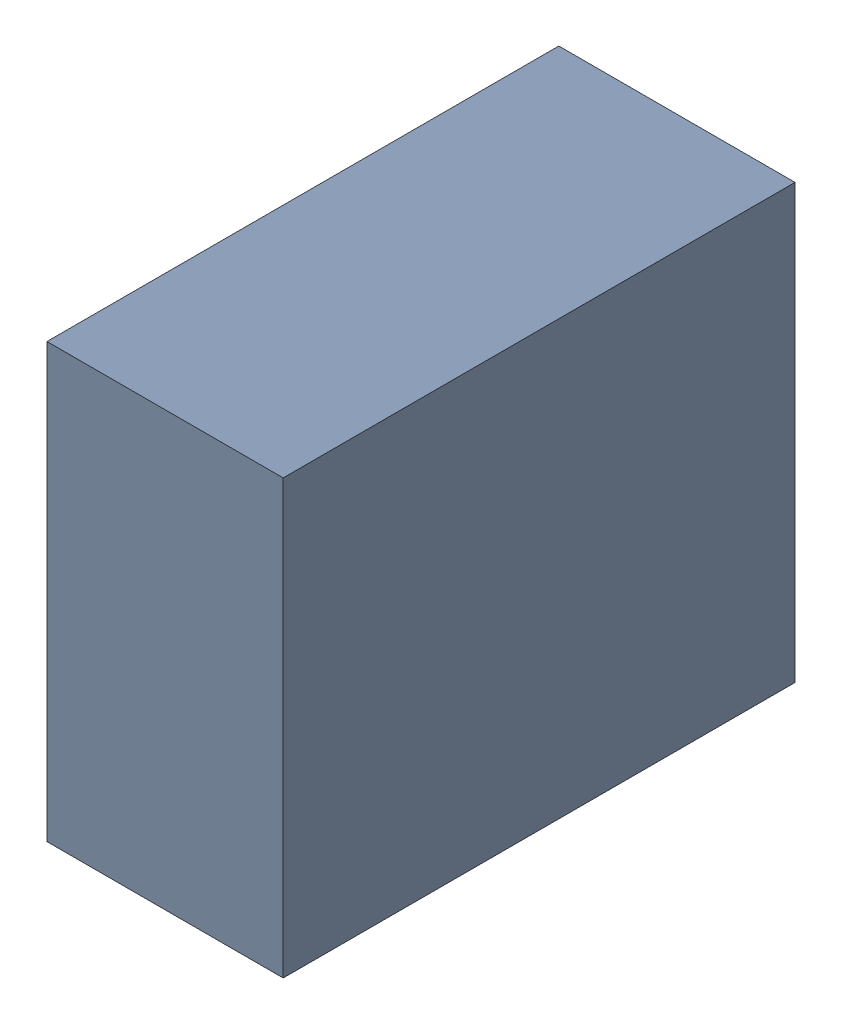
SolidWorks assembly C30_TDA1, configuration Standard. Lengths in mm.
Overall size (0.6 1.1 1.3).
2 component instances, 1 part files, 0 mates.
Components (placement in the parent):
- 885542376-1: 885542376 [Standard] at (4.2 58.62 0) size (0.6 1.1 1.3)
  - Extruded_25-1: Extruded_25 [Standard] at origin size (0.6 1.1 1.3)
